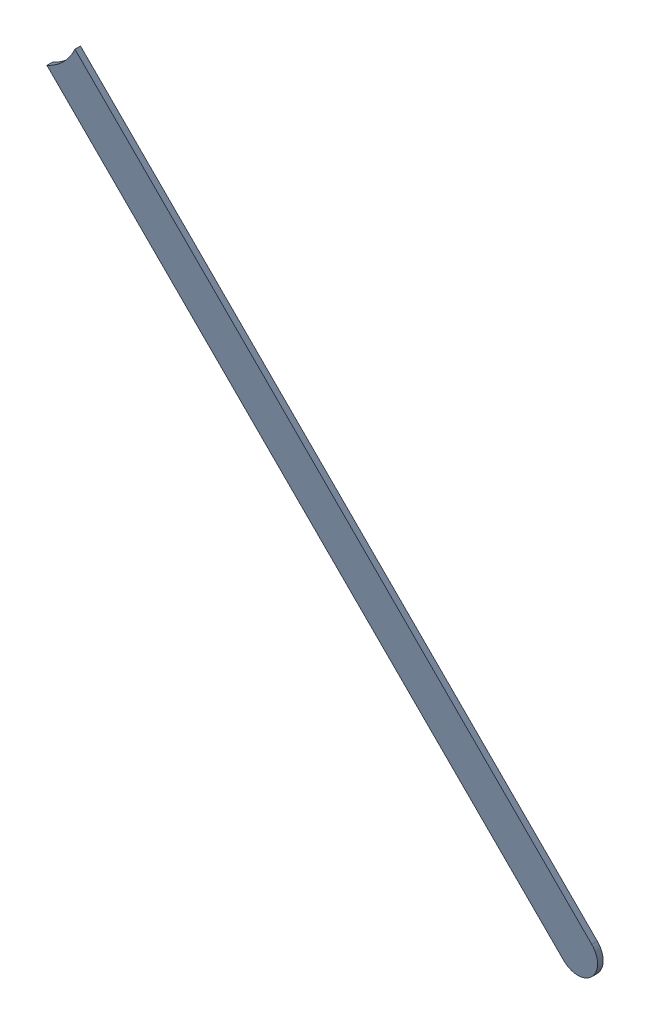
SolidWorks assembly Track (23.4mm,46.4mm)(26.95mm,42.85mm) on Top Layer, configuration Predeterminado. Lengths in mm.
Overall size (3.53 3.53 0.04).
2 component instances, 1 part files, 0 mates.
Components (placement in the parent):
- Track (23.4mm,46.4mm)(26.95mm,42.85mm) on Top Layer-1-1: Track (23.4mm,46.4mm)(26.95mm,42.85mm) on Top Layer-1 [Predeterminado] at (-68.317 -44.187 -0.0457) size (3.53 3.53 0.04)
  - Track (23.4mm,46.4mm)(26.95mm,42.85mm) on Top Layer-Part-1-1: Track (23.4mm,46.4mm)(26.95mm,42.85mm) on Top Layer-Part-1 [Predeterminado] at origin size (3.53 3.53 0.04)
